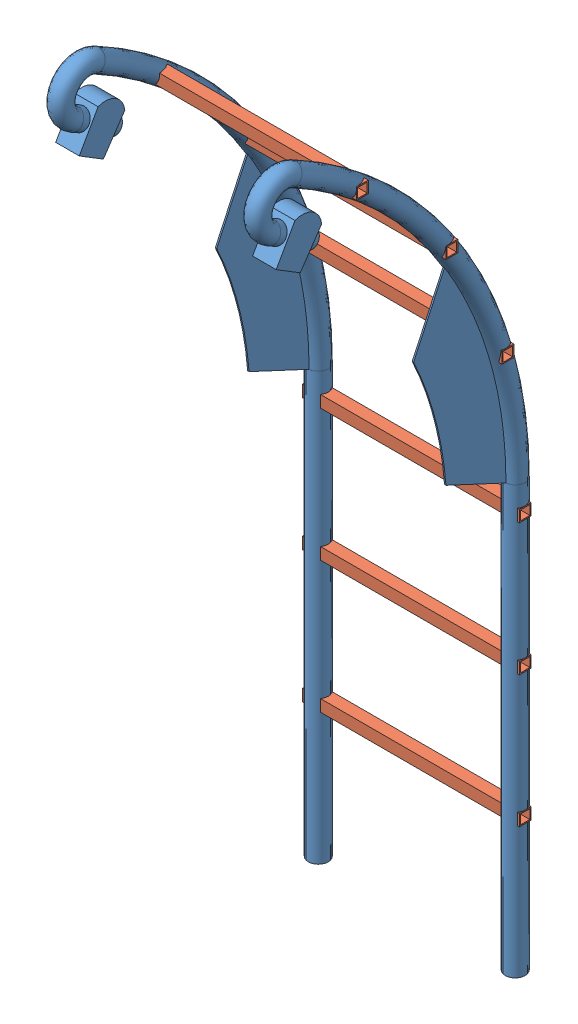
SolidWorks assembly External Ladder, configuration Default. Lengths in mm.
Overall size (467.8 1727.69 923.2).
8 component instances, 2 part files, 22 mates.
Components (placement in the parent):
- Ladder Pipe-1: Ladder Pipe [Default] at (0 899.373 2023.0346) size (50 1727.69 588.5)
- Ladder Pipe-2: Ladder Pipe [Default] at (417.8 899.373 2023.0346) size (50 1727.69 588.5)
- Ladder Rungs-1: Ladder Rungs [Default] at (208.9 1609.0727 1466.1587) size (460 25 25)
- Ladder Rungs-2: Ladder Rungs [Default] at (208.9 1405.589 1276.3554) size (460 25 25)
- Ladder Rungs-3: Ladder Rungs [Default] at (208.9 1153.8152 1157.5615) size (460 25 25)
- Ladder Rungs-4: Ladder Rungs [Default] at (208.9 844.073 1120.9346) size (460 25 25)
- Ladder Rungs-5: Ladder Rungs [Default] at (208.9 564.673 1120.9346) size (460 25 25)
- Ladder Rungs-6: Ladder Rungs [Default] at (208.9 285.273 1120.9346) size (460 25 25)
Mates (geometry in assembly coordinates):
- Coincident2: coincident aligned: plane of Ladder Pipe-1 through (0 899.373 2023.0346) normal (1 0 0)
- Distance1: distance = 417.8 mm aligned: plane of Ladder Pipe-1 through (0 899.373 2023.0346) normal (1 0 0); plane of Ladder Pipe-2 through (417.8 899.373 2023.0346) normal (1 0 0)
- Coincident3: coincident aligned: plane of Ladder Pipe-1 through (0 899.373 2023.0346) normal (0 0 1); plane of Ladder Pipe-2 through (417.8 899.373 2023.0346) normal (0 0 1)
- Coincident5: coincident aligned: plane of Ladder Pipe-1 through (0 899.373 2023.0346) normal (0 1 0); plane of Ladder Pipe-2 through (417.8 899.373 2023.0346) normal (0 1 0)
- Coincident6: coincident anti-aligned: plane of Ladder Pipe-2 through (392.8 272.773 1108.4346) normal (0 0 1); plane of Ladder Rungs-6 through (438.9 297.773 1108.4346) normal (0 0 -1)
- Coincident7: coincident anti-aligned: plane of Ladder Pipe-2 through (392.8 272.773 1108.4346) normal (0 1 0); plane of Ladder Rungs-6 through (438.9 272.773 1133.4346) normal (0 -1 0)
- Distance2: distance = 21.1 mm aligned: plane of Ladder Rungs-6 through (438.9 285.273 1120.9346) normal (1 0 0); plane of Ladder Pipe-2 through (417.8 899.373 2023.0346) normal (1 0 0)
- Coincident8: coincident anti-aligned: plane of Ladder Pipe-2 through (392.8 577.173 1108.4346) normal (0 0 1); plane of Ladder Rungs-5 through (438.9 577.173 1108.4346) normal (0 0 -1)
- Coincident9: coincident anti-aligned: plane of Ladder Pipe-2 through (392.8 577.173 1133.4346) normal (0 -1 0); plane of Ladder Rungs-5 through (438.9 577.173 1133.4346) normal (0 1 0)
- Distance3: distance = 21.1 mm aligned: plane of Ladder Rungs-5 through (438.9 564.673 1120.9346) normal (1 0 0); plane of Ladder Pipe-2 through (417.8 899.373 2023.0346) normal (1 0 0)
- Coincident10: coincident anti-aligned: plane of Ladder Pipe-2 through (392.8 831.573 1133.4346) normal (0 1 0); plane of Ladder Rungs-4 through (438.9 831.573 1133.4346) normal (0 -1 0)
- Coincident11: coincident anti-aligned: plane of Ladder Pipe-2 through (392.8 856.573 1133.4346) normal (0 0 -1); plane of Ladder Rungs-4 through (438.9 856.573 1133.4346) normal (0 0 1)
- Distance4: distance = 21.1 mm aligned: plane of Ladder Rungs-4 through (438.9 844.073 1120.9346) normal (1 0 0); plane of Ladder Pipe-2 through (417.8 899.373 2023.0346) normal (1 0 0)
- Coincident12: coincident anti-aligned: plane of Ladder Pipe-2 through (392.8 1141.3152 1170.0615) normal (0 1 0); plane of Ladder Rungs-3 through (438.9 1141.3152 1170.0615) normal (0 -1 0)
- Coincident13: coincident anti-aligned: plane of Ladder Pipe-2 through (392.8 1166.3152 1145.0615) normal (0 0 1); plane of Ladder Rungs-3 through (438.9 1166.3152 1145.0615) normal (0 0 -1)
- Distance5: distance = 21.1 mm aligned: plane of Ladder Pipe-2 through (417.8 899.373 2023.0346) normal (1 0 0); plane of Ladder Rungs-3 through (438.9 1153.8152 1157.5615) normal (1 0 0)
- Coincident15: coincident anti-aligned: plane of Ladder Pipe-2 through (392.8 1621.5727 1478.6587) normal (0 0 -1); plane of Ladder Rungs-1 through (438.9 1621.5727 1478.6587) normal (0 0 1)
- Coincident16: coincident anti-aligned: plane of Ladder Pipe-2 through (392.8 1621.5727 1478.6587) normal (0 -1 0); plane of Ladder Rungs-1 through (438.9 1621.5727 1478.6587) normal (0 1 0)
- Distance6: distance = 21.1 mm aligned: plane of Ladder Rungs-1 through (438.9 1609.0727 1466.1587) normal (1 0 0); plane of Ladder Pipe-2 through (417.8 899.373 2023.0346) normal (1 0 0)
- Coincident17: coincident anti-aligned: plane of Ladder Pipe-2 through (392.8 1418.089 1288.8554) normal (0 -1 0); plane of Ladder Rungs-2 through (438.9 1418.089 1288.8554) normal (0 1 0)
- Coincident18: coincident anti-aligned: plane of Ladder Pipe-2 through (392.8 1418.089 1263.8554) normal (0 0 1); plane of Ladder Rungs-2 through (438.9 1418.089 1263.8554) normal (0 0 -1)
- Distance7: distance = 21.1 mm aligned: plane of Ladder Rungs-2 through (438.9 1405.589 1276.3554) normal (1 0 0); plane of Ladder Pipe-2 through (417.8 899.373 2023.0346) normal (1 0 0)
